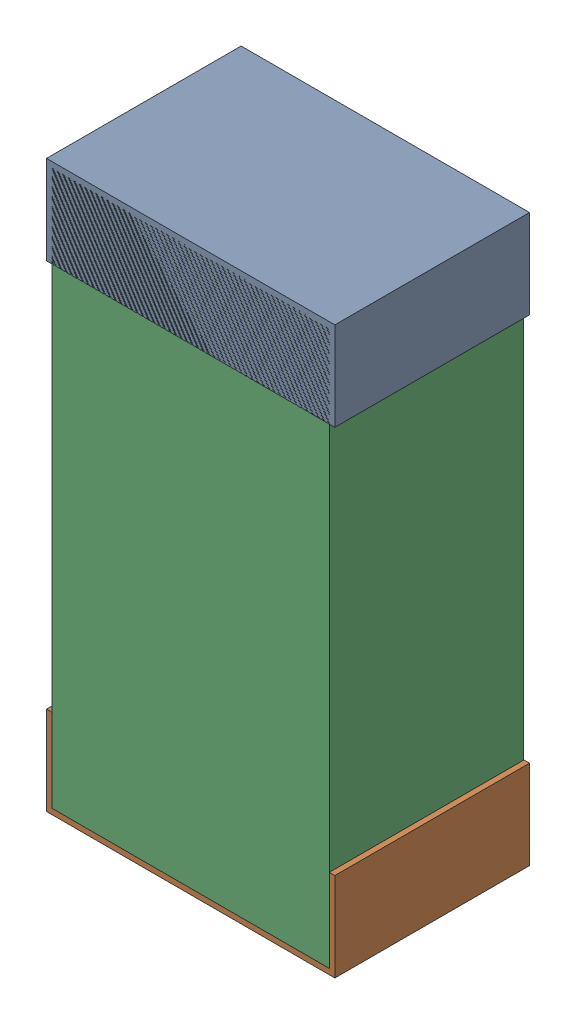
SolidWorks assembly C31, configuration Default. Lengths in mm.
Overall size (0.52 1.02 0.35).
6 component instances, 2 part files, 0 mates.
Components (placement in the parent):
- 870941120-1: 870941120 [Default] at (11.607 19.554 -1.9516) size (0.52 0.16 0.35)
  - Extruded_3-1: Extruded_3 [Default] at origin size (0.52 0.16 0.35)
- 870941120-2: 870941120 [Default] at (11.607 18.694 -1.9516) size (0.52 0.16 0.35)
  - Extruded_3-1: Extruded_3 [Default] at origin size (0.52 0.16 0.35)
- 870941280-1: 870941280 [Default] at (11.607 19.124 -1.9506) size (0.5 1 0.35)
  - Extruded_4-1: Extruded_4 [Default] at origin size (0.5 1 0.35)
